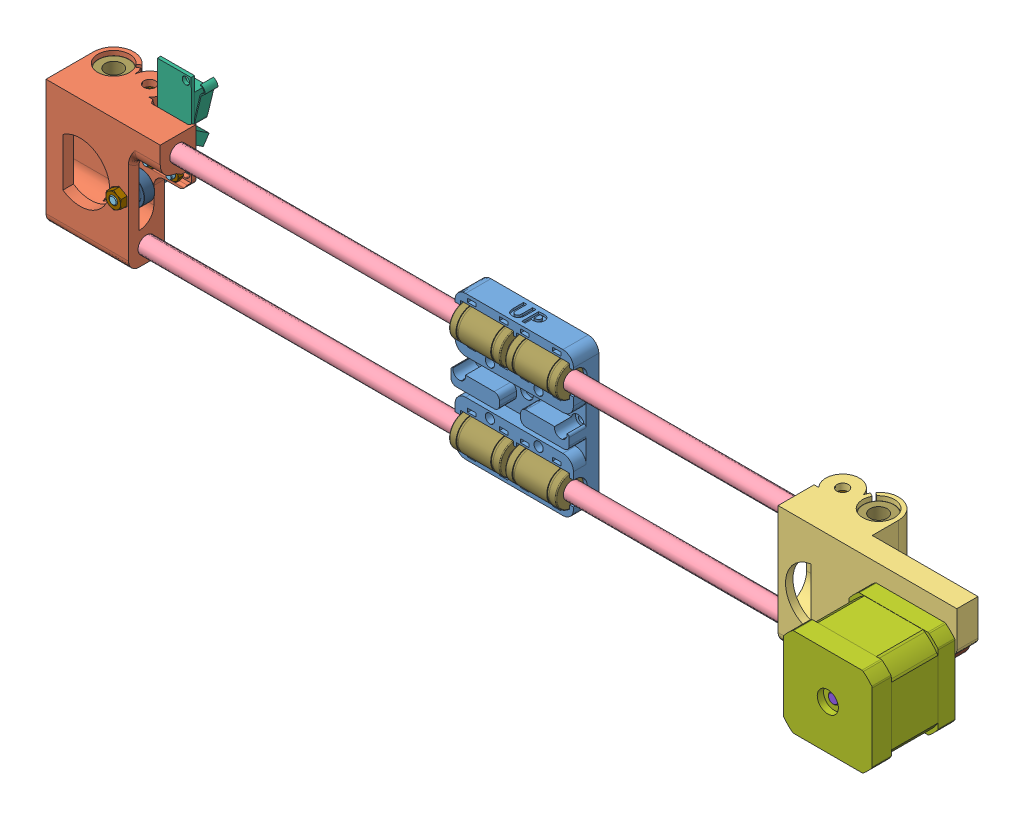
SolidWorks assembly Traverse axis, configuration Default. Lengths in mm.
Overall size (443.18 81.92 98.02).
30 component instances, 12 part files, 39 mates.
Components (placement in the parent):
- X-CARRIAGE_Universal-0.1-1: X-CARRIAGE_Universal-0.1 [Default] at (21.9957 -0.8838 -0.419) size (71.43 75.53 72.93)
- end-idler-0.1-1: end-idler-0.1 [Default] at (-152.8642 29.1162 5.081) x (0 1 0) z (1 0 0) size (60 40.87 54)
- end-motor-0.1-1: end-motor-0.1 [Default] at (227.7275 27.6162 5.081) x (-1 0 0) z (0 1 0) size (109.4 31.99 65.52)
- 8x370-Sm_Rod-1: 8x370-Sm_Rod [Default] at (-182.9646 21.6162 -3.419) x (0 0.354283 0.935138) z (-1 0 0) size (8 8 370)
- 8x370-Sm_Rod-2: 8x370-Sm_Rod [Default] at (-182.9646 -23.3838 -3.419) x (0 -0.426874 -0.904311) z (-1 0 0) size (8 8 370)
- Socket head cap screw-1: Socket head cap screw [M3x12] at (201.3267 -17.3838 -6.919) x (0 0 1) z (-1 0 0) size (15 5.5 5.5)
- Socket head cap screw-2: Socket head cap screw [M3x12] at (232.3267 13.6162 -6.919) x (0 0 1) z (-1 0 0) size (15 5.5 5.5)
- Socket head cap screw-3: Socket head cap screw [M3x12] at (201.3267 13.6162 -6.919) x (0 0 1) z (-1 0 0) size (15 5.5 5.5)
- Socket head cap screw-4: Socket head cap screw [DIN 912 M4 x 20 --- 20N] at (-157.3642 -1.8838 -15.919) x (0 0 1) z (0.55411 0.832443 0) size (24 7 7)
- Socket head cap screw-5: Socket head cap screw [M3x10] at (-142.7007 9.5193 -16.6079) x (0 0 1) z (-0.431421 0.902151 0) size (13 5.5 5.5)
- Socket head cap screw-6: Socket head cap screw [M3x10] at (-153.7006 9.4905 -16.6079) x (0 0 1) z (-0.975917 -0.218143 0) size (13 5.5 5.5)
- Mech endstop-1: Mech endstop [Default] at (-148.2465 27.0048 -12.0079) x (-0.002619 0.999997 0) z (0 0 -1) size (40 21.02 12.37)
- Stepper_motor_NEMA17 39mm-1: Stepper_motor_NEMA17 39mm [Default] at (216.8267 -1.8838 3.081) x (1 0 0) z (0 1 0) size (42 63.3 42)
  - Stator-1: Stator [Default] at origin size (42 41.1 42)
  - Rotor-1: Rotor [Default] x (0.508449 0 0.861092) z (-0.861092 0 0.508449) size (21 60.8 21)
- Hex nut-1: Hex nut [M5 Hex Nut] at (-166.1768 21.4162 -17) x (-0.498592 0 -0.866837) z (0 -1 0) size (8 9.24 4.7)
- Hex nut-2: Hex nut [M5 Hex Nut] at (162.2275 19.9162 -17.419) x (0.999996 0 0.002672) z (0 -1 0) size (8 9.24 4.7)
- Hex nut-3: Hex nut [M4 Hex Nut] at (-157.3642 -1.8838 7.804) x (0.504676 0.863309 0) z (0 0 1) size (7 8.08 3.2)
- Hex nut-4: Hex nut [M3 Hex Nut] at (-142.7007 9.5193 -5.4494) x (0.857251 -0.514899 0) z (0 0 1) size (5.5 6.35 2.4)
- Hex nut-6: Hex nut [M3 Hex Nut] at (-153.7006 9.4905 -5.4473) x (0.868758 0.495237 0) z (0 0 1) size (5.5 6.35 2.4)
- 4mm Bearing SKF 624 RS 286-7798-1: 4mm Bearing SKF 624 RS 286-7798 [Default] at (-157.3642 -1.8838 -0.3791) x (0 0 1) z (-0.999674 0.025514 0) size (5 13 13)
- GT2_20T-pulley 5mm bore-1: GT2_20T-pulley 5mm bore [Default] at (216.8267 -1.8838 -2.9492) x (0 0 -1) z (0.999848 0.01741 0) size (17.3 17 17)
- LMU8-5: LMU8 [Default] at (-182.3684 27.1162 -17.4178) x (0 -1 0) z (-0.165895 0 0.986143) size (24 15 15)
- LMU8-6: LMU8 [Default] at (179.2316 1.6162 -17.4178) x (0 -1 0) z (0 0 1) size (24 15 15)
- LMU8-1: LMU8 [Default] at (-2.2947 21.6162 -3.419) x (1 0 0) z (0 -0.01536 0.999882) size (24 15 15)
- LMU8-4: LMU8 [Default] at (-2.2947 -23.3838 -3.419) x (1 0 0) z (0 -0.01536 0.999882) size (24 15 15)
- LMU8-2: LMU8 [Default] at (24.2053 21.6162 -3.419) x (1 0 0) z (0 -0.01536 0.999882) size (24 15 15)
- LMU8-3: LMU8 [Default] at (24.2053 -23.3838 -3.419) x (1 0 0) z (0 -0.01536 0.999882) size (24 15 15)
- LMU8-7: LMU8 [Default] at (179.2316 25.6162 -17.4178) x (0 -1 0) z (-0.591671 0 0.80618) size (24 15 15)
- LMU8-8: LMU8 [Default] at (-182.3684 3.1162 -17.4178) x (0 -1 0) z (-0.98242 0 0.186681) size (24 15 15)
Mates (geometry in assembly coordinates):
- Coincident22: coincident anti-aligned: plane of LMU8-6 through (186.3316 1.6162 -17.4178) normal (0 1 0); plane of LMU8-7 through (182.4564 1.6162 -15.0511) normal (0 -1 0)
- Coincident20: coincident anti-aligned: plane of LMU8-5 through (-178.4238 3.1162 -16.7542) normal (0 -1 0); plane of LMU8-8 through (-181.0429 3.1162 -10.4426) normal (0 1 0)
- Concentric4: concentric anti-aligned: cylinder of LMU8-1 through (-2.2959 21.6162 -3.419) axis (1 0 0) radius 4; cylinder of 8x370-Sm_Rod-1 through (187.0354 21.6162 -3.419) axis (-1 0 0) radius 4
- Concentric1: concentric aligned: cylinder of X-CARRIAGE_Universal-0.1-1 through (-3.5043 21.6162 -3.419) axis (1 0 0) radius 7.5; cylinder of LMU8-1 through (-2.2959 21.6162 -3.419) axis (1 0 0) radius 7.5
- Concentric7: concentric anti-aligned: cylinder of LMU8-4 through (-2.2959 -23.3838 -3.419) axis (1 0 0) radius 4; cylinder of 8x370-Sm_Rod-2 through (187.0354 -23.3838 -3.419) axis (-1 0 0) radius 4
- Concentric8: concentric aligned: cylinder of end-motor-0.1-1 through (187.2275 -23.3838 -3.419) axis (-1 0 0) radius 4; cylinder of 8x370-Sm_Rod-2 through (187.0354 -23.3838 -3.419) axis (-1 0 0) radius 4
- Concentric44: concentric anti-aligned: cylinder of end-motor-0.1-1 through (179.2316 -29.3838 -17.4178) axis (0 1 0) radius 7.5042; cylinder of LMU8-7 through (179.2316 25.6175 -17.4178) axis (0 -1 0) radius 7.5
- Coincident23: coincident aligned: plane of end-motor-0.1-1 through (179.2316 -22.3838 -17.4178) normal (0 -1 0); plane of LMU8-6 through (183.2316 -22.3838 -17.4178) normal (0 -1 0)
- Concentric17: concentric aligned: cylinder of end-motor-0.1-1 through (232.3267 13.6162 9.3237) axis (0 0 -1) radius 1.5; cylinder of Socket head cap screw-2 through (232.3267 13.6162 -38.669) axis (0 0 -1) radius 1.5
- Coincident11: coincident anti-aligned: plane of end-motor-0.1-1 through (232.3267 13.6162 -3.919) normal (0 0 -1); plane of Socket head cap screw-2 through (232.3267 16.3662 -3.919) normal (0 0 1)
- Concentric18: concentric aligned: cylinder of end-motor-0.1-1 through (201.3267 13.6162 9.3237) axis (0 0 -1) radius 1.5; cylinder of Socket head cap screw-3 through (201.3267 13.6162 -38.669) axis (0 0 -1) radius 1.5
- Coincident12: coincident anti-aligned: plane of end-motor-0.1-1 through (201.3267 13.6162 -3.919) normal (0 0 -1); plane of Socket head cap screw-3 through (201.3267 16.3662 -3.919) normal (0 0 1)
- Concentric43: concentric anti-aligned: cylinder of end-motor-0.1-1 through (179.2316 -29.3838 -17.4178) axis (0 1 0) radius 7.5042; cylinder of LMU8-6 through (179.2316 1.6175 -17.4178) axis (0 -1 0) radius 7.5
- Concentric19: concentric aligned: cylinder of end-motor-0.1-1 through (201.3267 -17.3838 9.3237) axis (0 0 -1) radius 1.5; cylinder of Socket head cap screw-1 through (201.3267 -17.3838 -38.669) axis (0 0 -1) radius 1.5
- Coincident13: coincident anti-aligned: plane of end-motor-0.1-1 through (201.3267 -17.3838 -3.919) normal (0 0 -1); plane of Socket head cap screw-1 through (201.3267 -14.6338 -3.919) normal (0 0 1)
- Coincident17: coincident anti-aligned: plane of end-motor-0.1-1 through (188.7275 -29.3838 5.081) normal (0 0 1); plane of Stepper_motor_NEMA17 39mm-1/Stator-1 through (227.8267 -1.8838 5.081) normal (0 0 -1)
- Concentric29: concentric anti-aligned: cylinder of Mech endstop-1 through (-142.7007 9.5193 -13.6079) axis (0 0 1) radius 1.75; cylinder of Socket head cap screw-5 through (-142.7007 9.5193 -48.3579) axis (0 0 -1) radius 1.5
- Concentric30: concentric anti-aligned: cylinder of Mech endstop-1 through (-153.7006 9.4905 -13.6079) axis (0 0 1) radius 1.75; cylinder of Socket head cap screw-6 through (-153.7006 9.4905 -48.3579) axis (0 0 -1) radius 1.5
- Coincident18: coincident anti-aligned: plane of Mech endstop-1 through (-148.2465 27.0048 -13.6079) normal (0 0 -1); plane of Socket head cap screw-6 through (-154.3005 12.1743 -13.6079) normal (0 0 1)
- Coincident19: coincident anti-aligned: plane of Mech endstop-1 through (-148.2465 27.0048 -13.6079) normal (0 0 -1); plane of Socket head cap screw-5 through (-140.2197 10.7057 -13.6079) normal (0 0 1)
- Concentric28: concentric aligned: cylinder of Socket head cap screw-3 through (201.3267 13.6162 -38.669) axis (0 0 -1) radius 1.5; cylinder of Stepper_motor_NEMA17 39mm-1/Stator-1 through (201.3267 13.6162 11.081) axis (0 0 -1) radius 1.25
- Concentric27: concentric aligned: cylinder of Socket head cap screw-2 through (232.3267 13.6162 -38.669) axis (0 0 -1) radius 1.5; cylinder of Stepper_motor_NEMA17 39mm-1/Stator-1 through (232.3267 13.6162 11.081) axis (0 0 -1) radius 1.25
- Concentric31: concentric anti-aligned: cylinder of Socket head cap screw-5 through (-142.7007 9.5193 -48.3579) axis (0 0 -1) radius 1.5; cylinder of Hex nut-4 through (-142.7007 9.5193 -7.8494) axis (0 0 1) radius 1.25
- Concentric32: concentric anti-aligned: cylinder of Socket head cap screw-6 through (-153.7006 9.4905 -48.3579) axis (0 0 -1) radius 1.5; cylinder of Hex nut-6 through (-153.7006 9.4905 -7.8473) axis (0 0 1) radius 1.25
- Concentric36: concentric anti-aligned: cylinder of Socket head cap screw-4 through (-157.3642 -1.8838 -47.669) axis (0 0 -1) radius 2; cylinder of Hex nut-3 through (-157.3642 -1.8838 4.604) axis (0 0 1) radius 1.65
- Concentric37: concentric anti-aligned: cylinder of Socket head cap screw-4 through (-157.3642 -1.8838 -47.669) axis (0 0 -1) radius 2; cylinder of 4mm Bearing SKF 624 RS 286-7798-1 through (-157.3642 -1.8838 -0.3791) axis (0 0 1) radius 2
- Concentric39: concentric aligned: cylinder of Socket head cap screw-4 through (-157.3642 -1.8838 -47.669) axis (0 0 -1) radius 2; cylinder of ? through (-157.3642 -1.8838 0.7459) axis (0 0 -1) radius 2
- Concentric40: concentric anti-aligned: cylinder of Socket head cap screw-4 through (-157.3642 -1.8838 -47.669) axis (0 0 -1) radius 2; cylinder of ? through (-157.3642 -1.8838 -6.4283) axis (0 0 1) radius 2
- Concentric9: concentric anti-aligned: cylinder of end-idler-0.1-1 through (-222.6701 -23.3838 -3.419) axis (1 0 0) radius 4; cylinder of 8x370-Sm_Rod-2 through (187.0354 -23.3838 -3.419) axis (-1 0 0) radius 4
- Coincident14: coincident anti-aligned: plane of end-idler-0.1-1 through (-152.8642 -30.8838 -11.919) normal (0 0 -1); plane of Socket head cap screw-4 through (-154.4507 -3.8232 -11.919) normal (0 0 1)
- Concentric35: concentric aligned: circle of end-idler-0.1-1; cylinder of Socket head cap screw-4 through (-157.3642 -1.8838 -47.669) axis (0 0 -1) radius 2
- Concentric41: concentric anti-aligned: cylinder of end-idler-0.1-1 through (-182.3684 -30.8838 -17.4178) axis (0 1 0) radius 7.5042; cylinder of LMU8-8 through (-182.3684 3.1175 -17.4178) axis (0 -1 0) radius 7.5
- Concentric42: concentric anti-aligned: cylinder of end-idler-0.1-1 through (-182.3684 -30.8838 -17.4178) axis (0 1 0) radius 7.5042; cylinder of LMU8-5 through (-182.3684 27.1175 -17.4178) axis (0 -1 0) radius 7.5
- Coincident21: coincident aligned: plane of end-idler-0.1-1 through (-152.8642 -20.8838 5.081) normal (0 -1 0); plane of LMU8-8 through (-181.6216 -20.8838 -13.4881) normal (0 -1 0)
- Distance2: distance = 361.6 mm: axis of end-idler-0.1-1 through (-182.3684 -20.8838 -17.4178) axis (0 1 0); axis of end-motor-0.1-1 through (179.2316 -22.3838 -17.4178) axis (0 1 0)
- Coincident27: coincident anti-aligned: axis of end-motor-0.1-1 through (162.2275 19.6162 -17.419) axis (0 1 0); axis of Hex nut-2 through (162.2275 24.3107 -17.419) axis (0 -1 0)
- Coincident28: coincident anti-aligned: plane of end-motor-0.1-1 through (227.7275 24.6162 5.081) normal (0 -1 0); plane of Hex nut-2 through (154.2275 24.6162 -17.4404) normal (0 1 0)
- Coincident29: coincident anti-aligned: plane of end-idler-0.1-1 through (-152.8642 26.1162 5.081) normal (0 -1 0); plane of Hex nut-1 through (-162.188 26.1162 -10.0653) normal (0 1 0)
- Concentric46: concentric anti-aligned: cylinder of Stepper_motor_NEMA17 39mm-1/Rotor-1 through (216.8267 -1.8838 -19.119) axis (0 0 -1) radius 2.5; cylinder of GT2_20T-pulley 5mm bore-1 through (216.8267 -1.8838 2.0008) axis (0 0 1) radius 2.5
